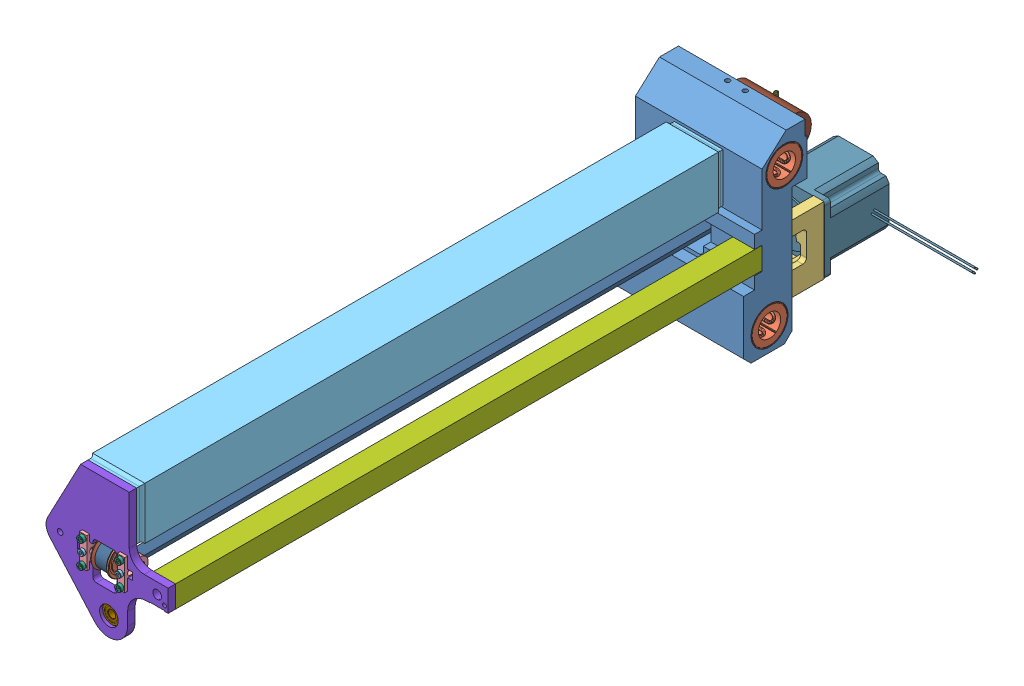
SolidWorks assembly B_Master_01, configuration Default. Lengths in mm.
Overall size (171.6 157.2 642.57).
43 component instances, 25 part files, 82 mates.
Components (placement in the parent):
- B0001_bearings-1: B0001_bearings [Default] at origin size (108 157.2 91.28)
  - B0001-1: B0001 [leadscrew nema23 variant] at origin size (108 157.2 53.97)
  - 3-4in_ss_6262K850-1: 3-4in_ss_6262K850 [6262K85] at (33.3625 111.985 -12.625) x (0 0 1) z (-1 0 0) size (31.75 31.75 41.27)
  - 3-4in_ss_6262K850-2: 3-4in_ss_6262K850 [6262K85] at (33.3625 0 0) x (0 0 1) z (-1 0 0) size (31.75 31.75 41.27)
  - 3-4in_ss_6262K850-3: 3-4in_ss_6262K850 [6262K85] at (-33.3625 0 0) x (0 0 1) z (-1 0 0) size (31.75 31.75 41.27)
  - 3-4in_ss_6262K850-4: 3-4in_ss_6262K850 [6262K85] at (-33.3625 111.985 -12.625) x (0 0 1) z (-1 0 0) size (31.75 31.75 41.27)
  - B-motor-mount-3-1: B-motor-mount-3 [Default<As Machined>] at (19.422 0.473 -44.1) x (0 0 -1) z (0 1 0) size (50 85 85)
  - M4x20_91292A121-1: M4x20_91292A121 [91292A121] at (26.922 26.298 -9.1) size (7 7 24.36)
  - M4x20_91292A121-2: M4x20_91292A121 [91292A121] at (26.922 67.473 -9.1) x (0.993992 -0.109453 0) z (0 0 1) size (7 7 24.36)
  - M4x20_91292A121-3: M4x20_91292A121 [91292A121] at (-7.5 -7.027 -9.1) size (7 7 24.36)
  - M4x20_91292A121-4: M4x20_91292A121 [91292A121] at (7.5 -9.027 -9.1) size (7 7 24.36)
- B0005-1: B0005 [Default] at (22.18 73.47 11.78) x (-1 0 0) z (0 0 1) size (44.53 44.53 500)
- B0006^B_Master_01-1: B0006^B_Master_01 [Default] at (0 57.72 0) x (-1 0 0) z (0 1 0) size (15.88 502 15.88) (virtual)
- B0003-2: B0003 [Default] at (53.865 43.605 6.37) x (-1 0 0) z (0 0 1) size (18.63 18.63 500)
- BR0002^B_Master_01-1: BR0002^B_Master_01 [Default] at origin size (104.17 115.86 6.35) (virtual)
- flanged_1-4x5-8x0-196in_4262T170-1: flanged_1-4x5-8x0-196in_4262T170 [4262T17] at (3.3 16.595 507.7824) size (17.53 17.53 4.98)
- Belt^B_Master_01-1: Belt^B_Master_01 [Default] x (0 0 -1) z (1 0 0) size (560.59 22 10) (virtual)
- EVA_nut_flats-1: EVA_nut_flats [Default] at (0 101.72 -49.645) x (0 0 -1) z (1 0 0) size (30 30 50)
- Leadscrew_flange^B_Master_01-1: Leadscrew_flange^B_Master_01 [Default] at (0 92.72 0) x (1 0 0) z (0 -1 0) size (25 44.84 1.59) (virtual)
- PulleyBearingFlange_01-1: PulleyBearingFlange_01 [Default] x (0 0 -1) z (1 0 0) size (32.17 42.66 6.35)
- PulleyBearingFlange_01-2: PulleyBearingFlange_01 [Default] at (26.7 0 0) x (0 0 -1) z (1 0 0) size (32.17 42.66 6.35)
- NEMA23_5718M-1: NEMA23_5718M [Default] at (3.3 16.595 -124.218) x (0 -1 0) z (0 0 1) size (57.15 142.88 75.69)
- flanged_10x15x4_F6700-2RS-1: flanged_10x15x4_F6700-2RS [Default] at (10.325 54.385 -34.645) x (0 1 0) z (0 0 1) size (16 4 16)
- flanged_10x15x4_F6700-2RS-2: flanged_10x15x4_F6700-2RS [Default] at (-10.025 54.385 -34.645) x (0 0.381849 -0.924225) z (0 -0.924225 -0.381849) size (16 4 16)
- M3x25_91292A020-1: M3x25_91292A020 [91292A020] at (0 116.1325 -59.645) x (1 0 0) z (0 1 0) size (5.5 5.5 28.2)
- M3x25_91292A020-2: M3x25_91292A020 [91292A020] at (0 116.1325 -39.645) x (1 0 0) z (0 1 0) size (5.5 5.5 28.2)
- M4x20_91292A121-1: M4x20_91292A121 [91292A121] at (7.5 111.1325 -25.79) x (1 0 0) z (0 1 0) size (7 7 24.36)
- M4x20_91292A121-2: M4x20_91292A121 [91292A121] at (-7.5 111.1325 -25.79) x (1 0 0) z (0 1 0) size (7 7 24.36)
- Pulley_MoldedAssm2-1: Pulley_MoldedAssm2 [Default] at (0 54.385 -34.645) x (1 0 0) z (0 0.098292 0.995158) size (28 19 19)
  - GT3x18_GPA18GT3090-A-H8-1: GT3x18_GPA18GT3090-A-H8 [Machined] at origin size (14 19 19)
  - Square_Insert^Pulley_MoldedAssm2-1: Square_Insert^Pulley_MoldedAssm2 [Default] at origin size (28 11 11) (virtual)
  - SpringPin_1x4_91611A065-1: SpringPin_1x4_91611A065 [Default] at (0 5.16 0) x (0 -1 0) z (0 0 1) size (4.02 1.01 1)
- AFDF15-20-1: AFDF15-20 [Default] at (0 55.7906 505.3532) size (15 25 25)
- PSFMRPL6-L26-F7-T4-1: PSFMRPL6-L26-F7-T4 [Default] at (0 55.7906 505.3532) size (40 6 6)
- PulleySlot-1: PulleySlot [Default] at (19.35 0 0) x (0 0 1) z (-1 0 0) size (20.02 26 6.35)
- PulleySlot-2: PulleySlot [Default] at (-19.35 111.5813 0) x (0 0 1) z (1 0 0) size (20.02 26 6.35)
- M2-6x15_SCB2-6-15-1: M2-6x15_SCB2-6-15 [91290A035] at (16 55.7906 500.21) x (-0.923728 -0.383049 0) z (0 0 -1) size (5 5 17.8)
- M2-6x15_SCB2-6-15-2: M2-6x15_SCB2-6-15 [91290A035] at (-16 55.7906 500.21) x (-0.923728 -0.383049 0) z (0 0 -1) size (5 5 17.8)
- M3x8_91292A112-1-1: M3x8_91292A112-1 [91292A112] at (-16.175 45.7906 507.21) x (-0.923728 -0.383049 0) z (0 0 -1) size (5.5 5.5 11.14)
- M3x8_91292A112-1-2: M3x8_91292A112-1 [91292A112] at (16.175 45.7906 507.21) x (-0.923728 -0.383049 0) z (0 0 -1) size (5.5 5.5 11.14)
- M3x8_91292A112-1-3: M3x8_91292A112-1 [91292A112] at (16.175 65.7906 507.21) x (-0.923728 -0.383049 0) z (0 0 -1) size (5.5 5.5 11.14)
- M3x8_91292A112-1-4: M3x8_91292A112-1 [91292A112] at (-16.175 65.7906 507.21) x (-0.923728 -0.383049 0) z (0 0 -1) size (5.5 5.5 11.14)
- 1-4x-14_ss_S50HWH-075H0808-1: 1-4x-14_ss_S50HWH-075H0808 [Default] at (3.3 16.595 -42.096) x (0.997893 -0.064874 0) z (0 0 1) size (19.05 19.05 22.86)
Mates (geometry in assembly coordinates):
- Coincident1: coincident aligned: plane of ? through (0 0 0) normal (0 0 1); plane of assembly through (0 0 0) normal (0 0 1)
- Coincident2: coincident aligned: plane of ? through (0 0 0) normal (0 1 0); plane of assembly through (0 0 0) normal (0 1 0)
- Coincident3: coincident aligned: plane of ? through (0 0 0) normal (1 0 0); plane of assembly through (0 0 0) normal (1 0 0)
- Concentric1: concentric anti-aligned: cylinder of ? through (-9.75 86.37 22.18) axis (0 0 -1) radius 2.6; line of B0005-1 through (-9.75 86.37 6.36) axis (0 0 1)
- Parallel1: parallel anti-aligned: plane of ? through (-54 73.61 12.73) normal (0 1 0); plane of B0005-1 through (22.18 73.47 500.94) normal (0 -1 0)
- Coincident8: coincident anti-aligned: plane of ? through (-54 73.61 6.36) normal (0 0 1); plane of B0005-1 through (-20.8 116.45 6.36) normal (0 0 -1)
- InPlace1: in place: plane of B0006^B_Master_01-1 through (0 57.72 0) normal (0 1 0); moOrthogonalPlaneRef_w of B0006^B_Master_01-1; line of B0006^B_Master_01-1 through (-55 0 57.72) axis (0 -1 0); unknown of B0006^B_Master_01-1
- Coincident11: coincident aligned: 
- Coincident12: coincident aligned: unknown of B0006^B_Master_01-1
- Coincident13: coincident anti-aligned: line of B0006^B_Master_01-1 through (-276.1 0 57.72) axis (0 -1 0)
- Parallel3: parallel aligned: plane of ? through (54 43 6.37) normal (0 1 0); plane of B0003-2 through (38.2 44.105 506.37) normal (0 1 0)
- Concentric4: concentric aligned: cylinder of ? through (44.55 52.92 22.18) axis (0 0 -1) radius 3.55; cylinder of B0003-2 through (44.55 52.92 30.37) axis (0 0 -1) radius 2.71
- Coincident15: coincident anti-aligned: plane of ? through (54 62.52 6.37) normal (0 0 1); plane of B0003-2 through (53.865 62.235 6.37) normal (0 0 -1)
- Coincident16: coincident anti-aligned: plane of ? through (33.415 75.02 506.36) normal (0 0 -1); plane of flanged_1-4x5-8x0-196in_4262T170-1 through (3.3 22.6302 506.36) normal (0 0 1)
- Concentric5: concentric anti-aligned: cylinder of ? through (3.3 16.595 512.71) axis (0 0 -1) radius 7.9375; cylinder of flanged_1-4x5-8x0-196in_4262T170-1 through (3.3 16.595 510.2716) axis (0 0 1) radius 7.9375
- InPlace2: in place: plane of ? through (0 0 0) normal (-1 0 0); line of ? through (-55 0 0) axis (0 0 1); plane of ? through (0 0 0) normal (0 0 1); unknown of ?
- Coincident19: coincident: 
- Coincident20: coincident aligned: line of ? through (-5.5 0 0) axis (0 0 1)
- Coincident21: coincident: plane of ? through (0 0 0) normal (0 0 -1)
- Concentric11: concentric aligned: cylinder of EVA_nut_flats-1 through (25 101.72 -49.645) axis (1 0 0) radius 15
- Parallel4: parallel aligned: plane of ? through (-54 43.53 22.18) normal (0 -1 0); plane of EVA_nut_flats-1 through (12.7 92.72 -34.645) normal (0 -1 0)
- Coincident21: coincident aligned: plane of EVA_nut_flats-1 through (0 101.72 -49.645) normal (1 0 0); plane of assembly through (0 0 0) normal (1 0 0)
- InPlace3: in place: plane of ? through (-54 92.72 -31.79) normal (0 -1 0); plane of Leadscrew_flange^B_Master_01-1 through (0 92.72 0) normal (0 -1 0); plane of ? through (-54 92.72 -31.79) normal (0 -1 0); plane of Leadscrew_flange^B_Master_01-1 through (0 92.72 0) normal (0 0 1); plane of ? through (-54 92.72 -31.79) normal (0 -1 0); line of Leadscrew_flange^B_Master_01-1 through (-55 0 92.72) axis (0 1 0); plane of ? through (-54 92.72 -31.79) normal (0 -1 0); unknown of Leadscrew_flange^B_Master_01-1
- Coincident22: coincident aligned: 
- Coincident23: coincident aligned: plane of ? through (0 92.72 0) normal (0 0 1); plane of Leadscrew_flange^B_Master_01-1 through (0 92.72 0) normal (0 0 1)
- Coincident24: coincident anti-aligned: plane of ? through (0 92.72 0) normal (-1 0 0); line of Leadscrew_flange^B_Master_01-1 through (-24.6647 0 92.72) axis (0 1 0)
- InPlace6: in place: plane of ? through (0 0 0) normal (1 0 0); line of ? through (-55 0 0) axis (0 0 1); plane of ? through (0 0 0) normal (0 0 -1); unknown of ?
- Coincident31: coincident aligned: 
- Coincident32: coincident aligned: line of ? through (-3.4925 0 0) axis (0 0 1)
- Coincident33: coincident anti-aligned: plane of ? through (0 0 0) normal (0 0 -1)
- Concentric12: concentric aligned: cylinder of ? through (13.5 41.72 -9.1) axis (0 0 -1) radius 2; cylinder of PulleyBearingFlange_01-2 through (13.5 41.72 -19.099) axis (0 0 -1) radius 2.325
- Concentric13: concentric aligned: cylinder of ? through (-10.025 54.385 -34.645) axis (-1 0 0) radius 7.5; cylinder of PulleyBearingFlange_01-2 through (16.675 54.385 -34.645) axis (-1 0 0) radius 7.5
- Concentric14: concentric aligned: cylinder of ? through (3.3 16.595 22.18) axis (0 0 -1) radius 7.875; cylinder of NEMA23_5718M-1 through (3.3 16.595 -48.526) axis (0 0 -1) radius 3.175
- Parallel5: parallel aligned: plane of ? through (-54 -20 -12.736) normal (0 -1 0); plane of NEMA23_5718M-1 through (-25.275 -11.98 -124.218) normal (0 -1 0)
- Coincident28: coincident anti-aligned: plane of PulleyBearingFlange_01-2 through (10.325 54.385 -34.645) normal (-1 0 0); plane of flanged_10x15x4_F6700-2RS-1 through (10.325 61.885 -34.645) normal (1 0 0)
- Coincident29: coincident anti-aligned: plane of ? through (-10.025 54.385 -34.645) normal (1 0 0); plane of flanged_10x15x4_F6700-2RS-2 through (-10.025 57.2489 -41.5767) normal (-1 0 0)
- Concentric16: concentric aligned: cylinder of ? through (-10.025 54.385 -34.645) axis (-1 0 0) radius 7.5; cylinder of flanged_10x15x4_F6700-2RS-2 through (-10.025 54.385 -34.645) axis (-1 0 0) radius 7.5
- Concentric17: concentric anti-aligned: cylinder of PulleyBearingFlange_01-2 through (16.675 54.385 -34.645) axis (-1 0 0) radius 7.5; cylinder of flanged_10x15x4_F6700-2RS-1 through (10.325 54.385 -34.645) axis (1 0 0) radius 5
- Coincident30: coincident anti-aligned: plane of Leadscrew_flange^B_Master_01-1 through (0 91.1325 -59.645) normal (0 -1 0); plane of M3x25_91292A020-1 through (0 91.1325 -59.645) normal (0 1 0)
- Coincident31: coincident anti-aligned: plane of Leadscrew_flange^B_Master_01-1 through (0 91.1325 -59.645) normal (0 -1 0); plane of M3x25_91292A020-2 through (0 91.1325 -39.645) normal (0 1 0)
- Concentric18: concentric aligned: cylinder of Leadscrew_flange^B_Master_01-1 through (0 91.1325 -59.645) axis (0 1 0) radius 1.6; cylinder of M3x25_91292A020-1 through (0 88.1325 -59.645) axis (0 1 0) radius 2.75
- Concentric19: concentric aligned: cylinder of Leadscrew_flange^B_Master_01-1 through (0 91.1325 -39.645) axis (0 1 0) radius 1.6; cylinder of M3x25_91292A020-2 through (0 88.1325 -39.645) axis (0 1 0) radius 2.75
- Coincident32: coincident anti-aligned: plane of Leadscrew_flange^B_Master_01-1 through (0 91.1325 -59.645) normal (0 -1 0); plane of M4x20_91292A121-1 through (7.5 91.1325 -25.79) normal (0 1 0)
- Coincident33: coincident anti-aligned: plane of Leadscrew_flange^B_Master_01-1 through (0 91.1325 -59.645) normal (0 -1 0); plane of M4x20_91292A121-2 through (-7.5 91.1325 -25.79) normal (0 1 0)
- Concentric20: concentric aligned: cylinder of Leadscrew_flange^B_Master_01-1 through (-7.5 91.1325 -25.79) axis (0 1 0) radius 2; cylinder of M4x20_91292A121-2 through (-7.5 87.1325 -25.79) axis (0 1 0) radius 3.5
- Concentric21: concentric aligned: cylinder of Leadscrew_flange^B_Master_01-1 through (7.5 91.1325 -25.79) axis (0 1 0) radius 2; cylinder of M4x20_91292A121-1 through (7.5 87.1325 -25.79) axis (0 1 0) radius 3.5
- Concentric22: concentric aligned: cylinder of ? through (0 54.385 -34.645) axis (1 0 0) radius 5.5
- Coincident34: coincident aligned: unknown of ?
- Coincident36: coincident aligned: plane of ? through (0 55.7906 505.3532) normal (1 0 0); plane of assembly through (0 0 0) normal (1 0 0)
- Concentric24: concentric anti-aligned: cylinder of ? through (0 55.7906 505.3532) axis (-1 0 0) radius 10
- Concentric25: concentric anti-aligned: cylinder of ? through (0 55.7906 505.3532) axis (-1 0 0) radius 3
- Coincident37: coincident aligned: plane of ? through (0 55.7906 505.3532) normal (1 0 0); plane of assembly through (0 0 0) normal (1 0 0)
- Parallel6: parallel anti-aligned: plane of ? through (20 53.5406 502.3532) normal (0 -1 0); plane of assembly through (0 0 0) normal (0 1 0)
- InPlace7: in place: plane of ? through (16.175 48.7906 506.36) normal (-1 0 0); plane of ? through (16.175 0 0) normal (-1 0 0); plane of ? through (16.175 48.7906 506.36) normal (-1 0 0); line of ? through (-55 16.175 0) axis (0 0 1); plane of ? through (16.175 48.7906 506.36) normal (-1 0 0); plane of ? through (16.175 0 0) normal (0 0 1); plane of ? through (19.35 48.7906 506.36) normal (-1 0 0); unknown of PulleySlot-1
- Coincident38: coincident aligned: 
- Coincident39: coincident aligned: plane of ? through (19.35 0 0) normal (0 1 0); line of PulleySlot-1 through (-3.4925 19.35 0) axis (0 0 1)
- Coincident40: coincident anti-aligned: plane of ? through (19.35 0 0) normal (0 0 -1); plane of PulleySlot-1 through (19.35 0 0) normal (0 0 1)
- Coincident41: coincident anti-aligned: plane of ? through (33.415 75.02 512.71) normal (0 0 1); plane of PulleySlot-2 through (-13 68.7906 512.71) normal (0 0 -1)
- Concentric26: concentric aligned: cylinder of ? through (-16 55.7906 502.3532) axis (0 0 1) radius 1.1; cylinder of PulleySlot-2 through (-16 55.7906 495.1933) axis (0 0 1) radius 1.45
- Parallel7: parallel anti-aligned: plane of ? through (-19.35 48.7906 506.36) normal (1 0 0); plane of PulleySlot-2 through (-19.35 55.7906 502.1943) normal (-1 0 0)
- Coincident43: coincident aligned: plane of M2-6x15_SCB2-6-15-1 through (16 55.7906 515.21) normal (0 0 -1); plane of M2-6x15_SCB2-6-15-2 through (-16 55.7906 515.21) normal (0 0 -1)
- Coincident45: coincident anti-aligned: plane of PulleySlot-2 through (-13 68.7906 515.21) normal (0 0 1); plane of M2-6x15_SCB2-6-15-2 through (-16 55.7906 515.21) normal (0 0 -1)
- Concentric29: concentric anti-aligned: cylinder of PulleySlot-2 through (-16 55.7906 495.1933) axis (0 0 1) radius 1.45; cylinder of M2-6x15_SCB2-6-15-2 through (-16 55.7906 517.81) axis (0 0 -1) radius 2.5
- Concentric30: concentric anti-aligned: cylinder of PulleySlot-1 through (16 55.7906 495.1933) axis (0 0 1) radius 1.45; cylinder of M2-6x15_SCB2-6-15-1 through (16 55.7906 517.81) axis (0 0 -1) radius 2.5
- Coincident46: coincident aligned: plane of M3x8_91292A112-1-2 through (16.175 45.7906 515.21) normal (0 0 -1); plane of M3x8_91292A112-1-1 through (-16.175 45.7906 515.21) normal (0 0 -1)
- Coincident47: coincident aligned: plane of M3x8_91292A112-1-2 through (16.175 45.7906 515.21) normal (0 0 -1); plane of M3x8_91292A112-1-4 through (-16.175 65.7906 515.21) normal (0 0 -1)
- Coincident48: coincident aligned: plane of M3x8_91292A112-1-2 through (16.175 45.7906 515.21) normal (0 0 -1); plane of M3x8_91292A112-1-3 through (16.175 65.7906 515.21) normal (0 0 -1)
- Coincident49: coincident anti-aligned: plane of PulleySlot-1 through (13 42.7906 515.21) normal (0 0 1); plane of M3x8_91292A112-1-2 through (16.175 45.7906 515.21) normal (0 0 -1)
- Concentric31: concentric anti-aligned: cylinder of PulleySlot-2 through (-16.175 65.7906 495.1933) axis (0 0 1) radius 1.7; cylinder of M3x8_91292A112-1-4 through (-16.175 65.7906 518.21) axis (0 0 -1) radius 2.75
- Concentric32: concentric anti-aligned: cylinder of PulleySlot-1 through (16.175 65.7906 495.1933) axis (0 0 1) radius 1.7; cylinder of M3x8_91292A112-1-3 through (16.175 65.7906 518.21) axis (0 0 -1) radius 2.75
- Concentric33: concentric anti-aligned: cylinder of PulleySlot-2 through (-16.175 45.7906 495.1933) axis (0 0 1) radius 1.7; cylinder of M3x8_91292A112-1-1 through (-16.175 45.7906 518.21) axis (0 0 -1) radius 2.75
- Concentric34: concentric anti-aligned: cylinder of PulleySlot-1 through (16.175 45.7906 495.1933) axis (0 0 1) radius 1.7; cylinder of M3x8_91292A112-1-2 through (16.175 45.7906 518.21) axis (0 0 -1) radius 2.75
- Coincident52: coincident anti-aligned: plane of B0001_bearings-1/B-motor-mount-3-1 through (-52.578 -10.527 -69.1) normal (0 0 -1); plane of NEMA23_5718M-1 through (-25.275 -11.98 -69.1) normal (0 0 1)
- Concentric37: concentric aligned: cylinder of NEMA23_5718M-1 through (3.3 16.595 -48.526) axis (0 0 -1) radius 3.175; cylinder of 1-4x-14_ss_S50HWH-075H0808-1 through (3.3 16.595 -29.523) axis (0 0 -1) radius 3.175
- Distance1: distance = 5 mm anti-aligned: plane of 1-4x-14_ss_S50HWH-075H0808-1 through (3.3 16.595 -53.526) normal (0 0 -1); plane of NEMA23_5718M-1 through (3.3 16.595 -48.526) normal (0 0 1)
- PLANE2: unknown = 40.8977 mm: plane of ? through (10.3 64.2 22.18) normal (-1 0 0); plane of ? through (-10.3 64.2 22.18) normal (1 0 0)
- Sketch3: unknown: axis of B0001_bearings-1/3-4in_ss_6262K850-4 through (-53.2301 111.985 -12.625) axis (-1 0 0); unknown of ?; unknown of ?; line of ? through (-5 54.385 -34.645) axis (1 0 0); unknown of ?; unknown of ?; unknown of ?; unknown of ?; unknown of ?; unknown of EVA_nut_flats-1; unknown of ?; unknown of ?; unknown of EVA_nut_flats-1; unknown of EVA_nut_flats-1; unknown of EVA_nut_flats-1; unknown of EVA_nut_flats-1; unknown of ?; unknown of ?
- Axis2: unknown: cylinder of EVA_nut_flats-1 through (25 101.72 -49.645) axis (1 0 0) radius 5
- Axis4: unknown: cylinder of ? through (-13.2 73.72 -9.1) axis (0 0 -1) radius 2
- Axis6: unknown: cylinder of ? through (13.5 73.72 -9.1) axis (0 0 -1) radius 2
- PLANE4: unknown: plane of ? through (10.3 64.2 22.18) normal (-1 0 0)
- PLANE5: unknown: plane of ? through (10.3 64.2 22.18) normal (-1 0 0); unknown of ?; unknown of ?; unknown of ?; unknown of ?; unknown of ?; unknown of ?; unknown of ?; unknown of ?; unknown of ?; unknown of ?; unknown of ?; unknown of ?
